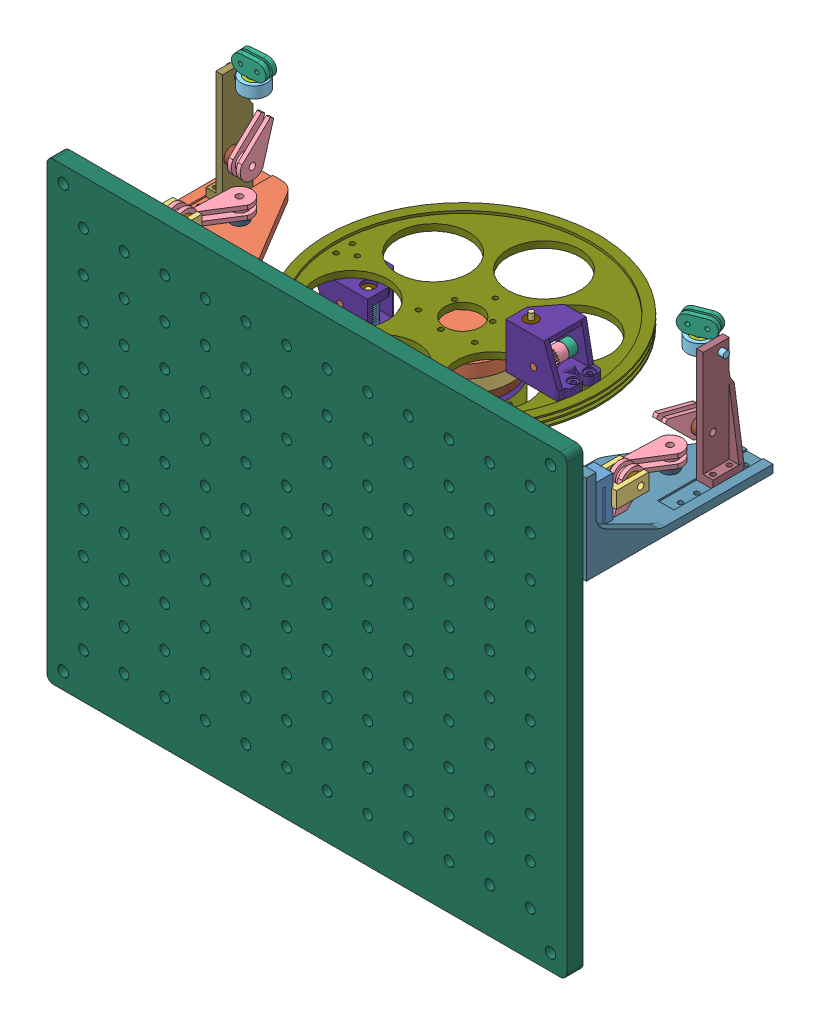
SolidWorks assembly 板套装3.0, configuration 默认. Lengths in mm.
Overall size (324 292.5 286.58).
90 component instances, 39 part files, 9 mates.
Components (placement in the parent):
- 拉力组件-1: 拉力组件 [默认] at (-415.5541 -217.674 3032.0178) x (-1 0 0) z (0 -1 0) size (57 115 93.17) (flexible)
  - 拉力计-1: 拉力计 [Default] at (-50.9646 32.0178 -6) x (0 0 -1) z (0 1 0) size (25 11.8 30)
  - 六角柱与拉力机连接板-1: 六角柱与拉力机连接板 [默认] at (-69.3646 -2.9822 -25) size (57 115 55)
  - 拉力连接件-1: 拉力连接件 [默认] at (-56.8646 31.0178 -18.5) x (0 0 -1) z (1 0 0) size (10 20 18)
  - NT002滑轮-1: NT002滑轮 [默认] at (-61.8646 78.0178 -12) x (0.955567 0.294773 0) z (-0.294773 0.955567 0) size (15 8 35.78)
  - NT002滑轮-2: NT002滑轮 [默认] at (-55.3646 46.0178 -18.5) x (0 -0.861828 -0.5072) z (0 0.5072 -0.861828) size (15 8 35.78)
  - 万向绳-1: 万向绳 [默认] at (-52.8646 -5.1943 -42.9711) x (0 -1 0) z (1 0 0) size (16 18.5 26.37) (flexible)
    - 万向绳2-1: 万向绳2 [默认] at (-97.2122 22.5289 -4) size (16 7 24)
    - 万向绳1-1: 万向绳1 [默认] at (-93.4396 35.2789 0.5366) x (-0.058649 0 -0.998279) z (0 1 0) size (20 7 13.5)
    - 万向绳3-1: 万向绳3 [默认] at (-97.2122 27.0289 -4) size (11 2.5 11)
    - 万向绳4-1: 万向绳4 [默认] at (-97.2122 27.0289 -4) x (-0.837169 0 -0.546944) z (-0.546944 0 0.837169) size (8 5 8)
  - NT002滑轮-3: NT002滑轮 [默认] at (-58.3646 87.0178 -28.5) x (0 -0.853831 -0.520551) z (0 -0.520551 0.853831) size (15 8 35.78)
  - 拉力计滑轮垫片-1: 拉力计滑轮垫片 [默认] at (-52.8646 46.0178 -18.5) x (0 0.855913 -0.51712) z (0 -0.51712 -0.855913) size (10 2 10)
  - 滑轮1垫片-1: 滑轮1垫片 [默认] at (-61.8646 78.0178 -9.5) x (0.855913 -0.51712 0) z (-0.51712 -0.855913 0) size (10 4.5 10)
  - 滑轮2垫片-1: 滑轮2垫片 [默认] at (-52.8646 87.0178 -28.5) x (0 -0.855913 0.51712) z (0 0.51712 0.855913) size (10 4.5 10)
  - 拉力计滑轮垫片-2: 拉力计滑轮垫片 [默认] at (-62.8646 46.0178 -18.5) x (0 0.855913 -0.51712) z (0 -0.51712 -0.855913) size (10 2 10)
  - 滑轮2连接板2.0-2: 滑轮2连接板2.0 [默认] at (-41.3646 87.0178 -4) x (0 -1 0) z (1 0 0) size (19 70 10)
- 拉力组件右-1: 拉力组件右 [默认] at (-44.965 -217.674 3034.2237) x (-1 0 0) z (0 -1 0) size (57 115 93.17) (flexible)
  - 拉力计-1: 拉力计 [Default] at (44.6245 34.2237 -6) x (0 0 -1) z (0 1 0) size (25 11.8 30)
  - 拉力连接件-1: 拉力连接件 [默认] at (38.7245 33.2237 -18.5) x (0 0 -1) z (1 0 0) size (10 20 18)
  - NT002滑轮-1: NT002滑轮 [默认] at (43.7245 80.2237 -12) x (0.955567 0.294773 0) z (-0.294773 0.955567 0) size (15 8 35.78)
  - NT002滑轮-2: NT002滑轮 [默认] at (40.2245 48.2237 -18.5) x (0 -0.861828 -0.5072) z (0 0.5072 -0.861828) size (15 8 35.78)
  - 万向绳-1: 万向绳 [默认] at (34.9245 191.4358 -42.9711) x (0 1 0) z (-1 0 0) size (16 18.5 26.37) (flexible)
    - 万向绳2-1: 万向绳2 [默认] at (-97.2122 22.5289 -4) size (16 7 24)
    - 万向绳1-1: 万向绳1 [默认] at (-92.1831 35.2789 -0.9144) x (-0.375978 0 -0.926629) z (0 1 0) size (20 7 13.5)
    - 万向绳3-1: 万向绳3 [默认] at (-97.2122 27.0289 -4) size (11 2.5 11)
    - 万向绳4-1: 万向绳4 [默认] at (-97.2122 27.0289 -4) x (-0.837169 0 -0.546944) z (-0.546944 0 0.837169) size (8 5 8)
  - NT002滑轮-3: NT002滑轮 [默认] at (40.2245 89.2237 -28.5) x (0 0.495502 -0.868607) z (0 0.868607 0.495502) size (15 8 35.78)
  - 拉力计滑轮垫片-1: 拉力计滑轮垫片 [默认] at (42.7245 48.2237 -18.5) x (0 0.855913 -0.51712) z (0 -0.51712 -0.855913) size (10 2 10)
  - 滑轮1垫片-1: 滑轮1垫片 [默认] at (43.7245 80.2237 -9.5) x (0.855913 -0.51712 0) z (-0.51712 -0.855913 0) size (10 4.5 10)
  - 滑轮2连接板2.0右-1: 滑轮2连接板2.0右 [默认] at (23.2245 89.2237 -4) x (0 1 0) z (-1 0 0) size (19 70 10)
  - 滑轮2垫片-1: 滑轮2垫片 [默认] at (34.7245 89.2237 -28.5) x (0 0.855913 0.51712) z (0 -0.51712 0.855913) size (10 4.5 10)
  - 拉力计滑轮垫片-2: 拉力计滑轮垫片 [默认] at (32.7245 48.2237 -18.5) x (0 0.855913 -0.51712) z (0 -0.51712 -0.855913) size (10 2 10)
  - 六角柱与拉力机连接板右-2: 六角柱与拉力机连接板右 [默认] at (26.2245 -0.7763 -25) size (57 115 55)
- 定位板-1: 定位板 [默认] at (-221.1895 -286.674 3035) x (1 0 0) z (0 -1 0) size (320 10 280)
- 电机测试组件-1: 电机测试组件 [默认] at (17.2386 -262.6144 3181.5275) x (0 1 0) z (-0.924225 0 -0.381849) size (174 219.42 219.42)
  - 轮组2.0-1: 轮组2.0 [默认] at (56.4404 123.864 309.1516) x (0 -0.381849 0.924225) z (0 0.924225 0.381849) size (168 7.5 168)
  - 装配体-1: 装配体 [默认] at (78.4555 112.6983 239.544) x (1 0 0) z (0 0.924225 0.381849) size (32 33.9 26)
    - box - 0-1: box - 0 [默认] at (-1.5151 4.9306 23.8992) size (28 33.9 26)
    - bearing-1: bearing [默认] at (-12.3151 -9.9694 28.8992) x (0 0 1) z (-1 0 0) size (9 9 3)
    - bearing-2: bearing [默认] at (9.2849 -9.9694 28.8992) x (0 -0.428044 -0.903758) z (1 0 0) size (9 9 3)
    - 零件2-1: 零件2 [默认] at (-11.5151 -9.9694 28.8992) x (1 0 0) z (0 -0.101118 0.994874) size (20 9.82 9.8)
    - zhou1-1: zhou1 [默认] at (-5.5151 -0.5694 20.8992) x (1 0 0) z (0 -1 0) size (4 26 4)
    - zhou2-1: zhou2 [默认] at (-14.5151 -9.9694 28.8992) x (0 0 -1) z (1 0 0) size (3 3 30)
    - gear-1: gear [默认] at (-5.5151 -0.5694 31.3992) x (0 0 -1) z (0.913862 -0.406024 0) size (12 10.93 10.93)
    - 1-1: 1 [默认] at (-5.5151 -0.5694 23.8992) x (0.998523 -0.054325 0) z (0 0 1) size (9 9 2.5)
    - 2-1: 2 [默认] at (-5.5151 -0.5694 38.3992) x (0.999989 0.004731 0) z (0 0 1) size (9 9 5.5)
  - 装配体-2: 装配体 [默认] at (41.4254 66.8234 350.5792) x (-1 0 0) z (0 0.924225 0.381849) size (32 33.9 26)
    - box - 0-1: box - 0 [默认] at (-1.5151 4.9306 23.8992) size (28 33.9 26)
    - bearing-1: bearing [默认] at (-12.3151 -9.9694 28.8992) x (0 0 1) z (-1 0 0) size (9 9 3)
    - bearing-2: bearing [默认] at (9.2849 -9.9694 28.8992) x (0 -0.428044 -0.903758) z (1 0 0) size (9 9 3)
    - 零件2-1: 零件2 [默认] at (-11.5151 -9.9694 28.8992) x (1 0 0) z (0 -0.101118 0.994874) size (20 9.82 9.8)
    - zhou1-1: zhou1 [默认] at (-5.5151 -0.5694 20.8992) x (1 0 0) z (0 -1 0) size (4 26 4)
    - zhou2-1: zhou2 [默认] at (-14.5151 -9.9694 28.8992) x (0 0 -1) z (1 0 0) size (3 3 30)
    - gear-1: gear [默认] at (-5.5151 -0.5694 31.3992) x (0 0 -1) z (0.913862 -0.406024 0) size (12 10.93 10.93)
    - 1-1: 1 [默认] at (-5.5151 -0.5694 23.8992) x (0.998523 -0.054325 0) z (0 0 1) size (9 9 2.5)
    - 2-1: 2 [默认] at (-5.5151 -0.5694 38.3992) x (0.999989 0.004731 0) z (0 0 1) size (9 9 5.5)
  - 达秒 4310 减速电机 3D-1: 达秒 4310 减速电机 3D [默认] at (2.9404 123.864 309.1516) x (0 -0.924225 -0.381849) z (0 -0.381849 0.924225) size (76.5 46 76.5)
    - 达秒 4310 减速电机 3D 20221104.STEP-1: 达秒 4310 减速电机 3D 20221104.STEP [默认] at origin size (76.5 46 76.5)
      - 4310 ________________3D.STEP-1: 4310 ________________3D.STEP [默认] x (-1 0 0) z (0 0 -1) size (76.5 45 76.5)
        - 4310 ____________3D.STEP-1: 4310 ____________3D.STEP [默认] x (-1 0 0) z (0 0 -1) size (55.43 29.4 56)
        - 4310 __________________B.STEP-1: 4310 __________________B.STEP [默认] at (0 32 0) x (-0.5 0 0.866025) z (0.866025 0 0.5) size (56 3.5 56)
        - 4310 ____________B.STEP-1: 4310 ____________B.STEP [默认] at (0 14.5 0) x (0 0 -1) z (0 1 0) size (11 1.5 28.8)
        - 4310 ________B.STEP-1: 4310 ________B.STEP [默认] at (0 -7 0) x (0 0 -1) z (1 0 0) size (56 7 56)
        - 4310 ________________B.STEP-1: 4310 ________________B.STEP [默认] at (0 38 0) x (-1 0 0) z (0 0 1) size (56 5.9 56)
        - M2.5x10 ______________.STEP-1: M2.5x10 ______________.STEP [默认] at (-17.6777 -6.9 -17.6777) x (-0.608335 0 0.79368) z (-0.79368 0 -0.608335) size (5 10 5)
        - M2.5x8 ______________.STEP-1: M2.5x8 ______________.STEP [默认] at (0 37.9 -24.5) x (0.794624 0 0.607102) z (0.607102 0 -0.794624) size (5 7.7 5)
        - M2.5x8 ______________.STEP-2: M2.5x8 ______________.STEP [默认] at (21.2176 37.9 12.25) x (-0.923078 0 0.384613) z (0.384613 0 0.923078) size (5 7.7 5)
        - M2.5x8 ______________.STEP-3: M2.5x8 ______________.STEP [默认] at (-21.2176 37.9 12.25) x (0.128454 0 -0.991715) z (-0.991715 0 -0.128454) size (5 7.7 5)
        - M2.5x5 ______________.STEP-1: M2.5x5 ______________.STEP [默认] at (-24.1621 24.75 -13.95) x (0.497833 -0.092998 -0.862272) z (-0.046499 -0.995666 0.080538) size (5 5 5)
        - M1.6x3 ______________.STEP-1: M1.6x3 ______________.STEP [默认] at (-27.5 6.5 -3.5) x (0 -0.828384 0.56016) z (0 0.56016 0.828384) size (3 3 3)
        - M1.6x3 ______________.STEP-2: M1.6x3 ______________.STEP [默认] at (-27.5 6.5 3.5) x (0 -0.828384 0.56016) z (0 0.56016 0.828384) size (3 3 3)
        - M1.6x3 ______________.STEP-3: M1.6x3 ______________.STEP [默认] at (-27.5 21 -3.5) x (0 -0.828384 0.56016) z (0 0.56016 0.828384) size (3 3 3)
        - M1.6x3 ______________.STEP-4: M1.6x3 ______________.STEP [默认] at (-27.5 21 3.5) x (0 -0.828384 0.56016) z (0 0.56016 0.828384) size (3 3 3)
        - M2.5x10 ______________.STEP-2: M2.5x10 ______________.STEP [默认] at (17.6777 -6.9 -17.6777) x (-0.79368 0 -0.608335) z (0.608335 0 -0.79368) size (5 10 5)
        - M2.5x10 ______________.STEP-3: M2.5x10 ______________.STEP [默认] at (17.6777 -6.9 17.6777) x (0.608335 0 -0.79368) z (0.79368 0 0.608335) size (5 10 5)
        - M2.5x10 ______________.STEP-4: M2.5x10 ______________.STEP [默认] at (-17.6777 -6.9 17.6777) x (0.79368 0 0.608335) z (-0.608335 0 0.79368) size (5 10 5)
        - M2.5x5 ______________.STEP-2: M2.5x5 ______________.STEP [默认] at (24.1621 24.75 -13.95) x (0.497833 -0.092998 0.862272) z (-0.046499 -0.995666 -0.080538) size (5 5 5)
        - M2.5x5 ______________.STEP-3: M2.5x5 ______________.STEP [默认] at (0 24.75 27.9) x (-0.995666 -0.092998 0) z (0.092998 -0.995666 0) size (5 5 5)
        - M2.5x4 ______________.STEP-1: M2.5x4 ______________.STEP [默认] at (-13.435 -1.65 -13.435) size (4.7 5.61 4.7)
        - M2.5x4 ______________.STEP-2: M2.5x4 ______________.STEP [默认] at (13.435 -1.65 -13.435) x (0 0 1) z (-1 0 0) size (4.7 5.61 4.7)
        - M2.5x4 ______________.STEP-3: M2.5x4 ______________.STEP [默认] at (13.435 -1.65 13.435) x (-1 0 0) z (0 0 -1) size (4.7 5.61 4.7)
        - M2.5x4 ______________.STEP-4: M2.5x4 ______________.STEP [默认] at (-13.435 -1.65 13.435) x (0 0 -1) z (1 0 0) size (4.7 5.61 4.7)
      - 4310 __________________3D.STEP-1: 4310 __________________3D.STEP [默认] at (0 20.9 0) x (0.866025 0 -0.5) z (0.5 0 0.866025) size (58.06 5 58.06)
        - 4310 ______________3D.STEP-1: 4310 ______________3D.STEP [默认] at (0 18.1 0) x (-0.5 0 0.866025) z (0.866025 0 0.5) size (42.5 5 42.5)
      - g43_v1_1_220606a.STEP-1: g43_v1_1_220606a.STEP [默认] at (0 -0.15 0) x (0 0 -1) z (0 -1 0) size (49.13 53.2 8)
  - 达妙电机底座-1: 达妙电机底座 [默认] at (-4.0596 34.8345 299.4182) x (-1 0 0) z (0 -0.924225 -0.381849) size (76 90 110)
  - 转换口-1: 转换口 [默认] at (55.5335 180.0062 330.3957) x (0 -0.381849 0.924225) z (0 -0.924225 -0.381849) size (81.96 16 81.96)
    - 转换口卷筒一侧-1: 转换口卷筒一侧 [默认] at (1.8035 -2.4069 60) size (60 8 60)
    - 转换口电机一侧-1: 转换口电机一侧 [默认] at (1.8035 13.5931 60) x (-0.5 0 -0.866025) z (-0.866025 0 0.5) size (60 8 60)
Mates (geometry in assembly coordinates):
- 重合2: coincident anti-aligned: plane of 拉力组件-1/六角柱与拉力机连接板-1 through (-346.1895 -192.674 3035) normal (0 0 1); plane of 定位板-1 through (-221.1895 -286.674 3035) normal (0 0 -1)
- 重合4: coincident anti-aligned: plane of 拉力组件右-1/六角柱与拉力机连接板右-2 through (-71.1895 -192.674 3035) normal (0 0 1); plane of 定位板-1 through (-221.1895 -286.674 3035) normal (0 0 -1)
- 重合11: coincident: plane of 定位板-1 through (-221.1895 -286.674 3035) normal (0 0 -1); plane of 电机测试组件-1/达妙电机底座-1 through (-197.0019 -341.2044 3035) normal (0 0 1)
- 平行1: parallel: plane of 定位板-1 through (-61.1895 -426.674 3045) normal (1 0 0); plane of 电机测试组件-1/达妙电机底座-1 through (-267.0019 -265.2044 3030) normal (-1 0 0)
- 同心17: concentric anti-aligned: circle of 拉力组件右-1/六角柱与拉力机连接板右-2; circle of 定位板-1
- 同心18: concentric anti-aligned: circle of 拉力组件右-1/六角柱与拉力机连接板右-2; circle of 定位板-1
- 同心19: concentric anti-aligned: circle of 拉力组件-1/六角柱与拉力机连接板-1; circle of 定位板-1
- 同心20: concentric anti-aligned: circle of 拉力组件-1/六角柱与拉力机连接板-1; circle of 定位板-1
- 同心21: concentric anti-aligned: circle of 定位板-1; circle of 电机测试组件-1/达妙电机底座-1
